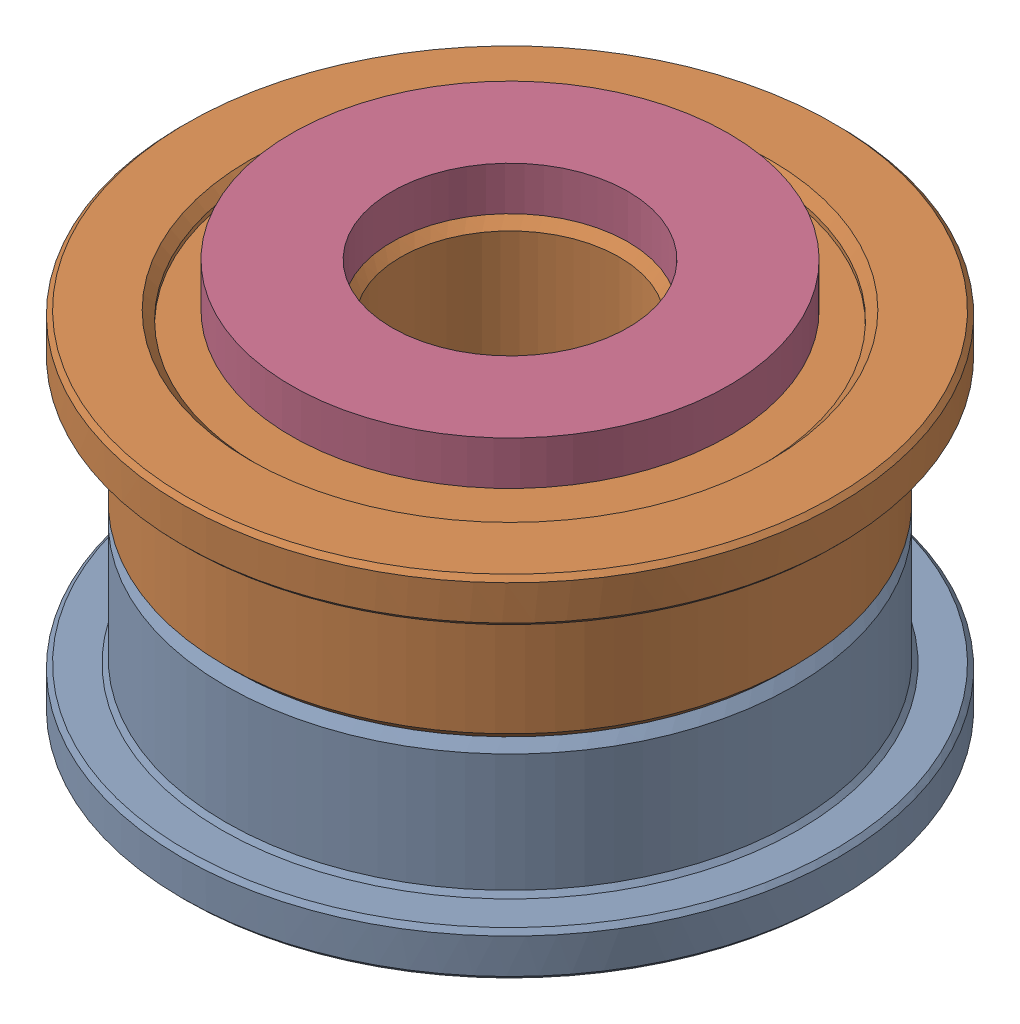
SolidWorks assembly Idler Pulley Assembly v3_4, configuration Default. Lengths in mm.
Overall size (15 10 15).
4 component instances, 3 part files, 0 mates.
Components (placement in the parent):
- F695-2RS v1 (1)-1: F695-2RS v1 (1) [Default] at origin size (15 4 15)
- F695-2RS v1 (2)-1: F695-2RS v1 (2) [Default] at (0 8 0) x (-1 0 0) z (0 0 1) size (15 4 15)
- M5 1mm Spacer-1: M5 1mm Spacer [Default] at (0 0 -350) size (10 1 10)
- M5 1mm Spacer-2: M5 1mm Spacer [Default] at (0 9 -350) size (10 1 10)
